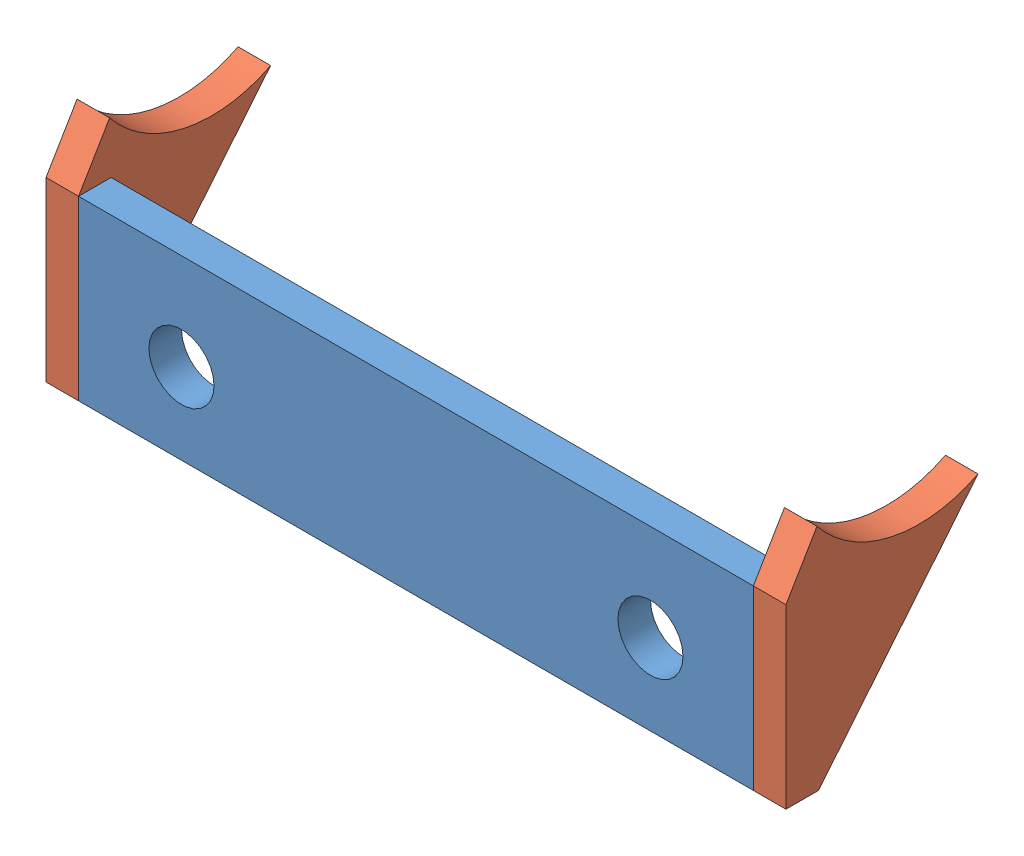
SolidWorks assembly ST-10001-AA-Steering Tab Box, configuration Default. Lengths in mm.
Overall size (72.14 22.37 18.72).
3 component instances, 2 part files, 6 mates.
Components (placement in the parent):
- Part1^ST-10001-AA-Steering Tab Box-1: Part1^ST-10001-AA-Steering Tab Box [Default] at origin size (65.79 17.27 3.17) (virtual)
- Part2^ST-10001-AA-Steering Tab Box-1: Part2^ST-10001-AA-Steering Tab Box [Default] at (32.893 -1.4041 5.7162) size (3.17 22.37 18.72) (virtual)
- Part2^ST-10001-AA-Steering Tab Box-2: Part2^ST-10001-AA-Steering Tab Box [Default] at (-36.068 -1.4041 5.7162) size (3.17 22.37 18.72) (virtual)
Mates (geometry in assembly coordinates):
- Coincident1: coincident anti-aligned: plane of Part1^ST-10001-AA-Steering Tab Box-1 through (32.893 -8.636 3.175) normal (1 0 0); plane of Part2^ST-10001-AA-Steering Tab Box-1 through (32.893 21.6362 -9.8019) normal (-1 0 0)
- Coincident2: coincident: plane of Part1^ST-10001-AA-Steering Tab Box-1 through (0 0 3.175) normal (0 0 1); plane of Part2^Assem1-1 through (33.02 -7.62 3.175) normal (0 0 1)
- Coincident3: coincident aligned: plane of Part1^ST-10001-AA-Steering Tab Box-1 through (-29.845 -8.636 3.175) normal (0 -1 0); plane of Part2^Assem1-1 through (33.02 -7.62 0) normal (0 -1 0)
- Coincident4: coincident anti-aligned: plane of Part1^ST-10001-AA-Steering Tab Box-1 through (-32.893 -8.636 3.175) normal (-1 0 0); plane of Part2^ST-10001-AA-Steering Tab Box-2 through (-32.893 21.6362 -9.8019) normal (1 0 0)
- Coincident5: coincident: plane of Part1^ST-10001-AA-Steering Tab Box-1 through (-29.845 -8.636 3.175) normal (0 -1 0); plane of Part2^Assem1-2 through (-29.845 -7.62 0) normal (0 -1 0)
- Coincident6: coincident aligned: plane of Part1^ST-10001-AA-Steering Tab Box-1 through (0 0 3.175) normal (0 0 1); plane of Part2^Assem1-2 through (-29.845 -7.62 3.175) normal (0 0 1)
